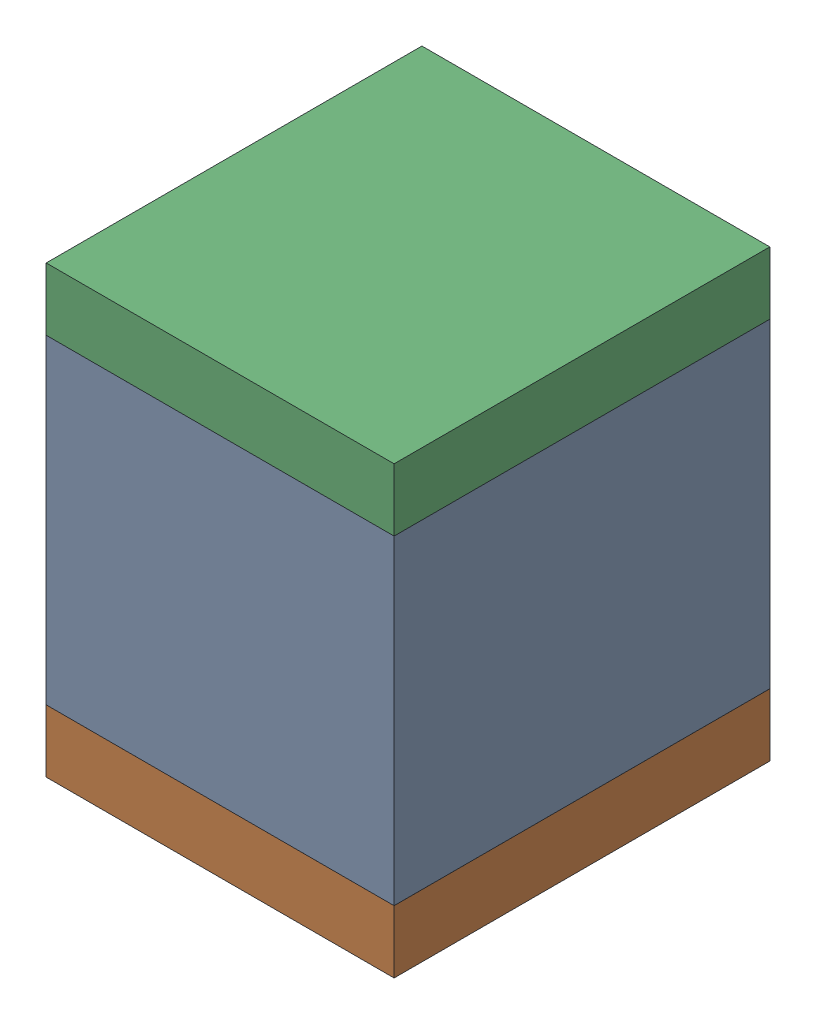
SolidWorks assembly C13, configuration ﾃﾞﾌｫﾙﾄ. Lengths in mm.
Overall size (2.5 3.2 2.7).
6 component instances, 2 part files, 0 mates.
Components (placement in the parent):
- 689260016-1: 689260016 [ﾃﾞﾌｫﾙﾄ] at (73.5 57.75 0) size (2.5 2.3 2.7)
  - Extruded_6-1: Extruded_6 [ﾃﾞﾌｫﾙﾄ] at origin size (2.5 2.3 2.7)
- 689260152-1: 689260152 [ﾃﾞﾌｫﾙﾄ] at (73.5001 56.375 0) size (2.5 0.45 2.7)
  - Extruded_7-1: Extruded_7 [ﾃﾞﾌｫﾙﾄ] at origin size (2.5 0.45 2.7)
- 689260152-2: 689260152 [ﾃﾞﾌｫﾙﾄ] at (73.5001 59.125 0) size (2.5 0.45 2.7)
  - Extruded_7-1: Extruded_7 [ﾃﾞﾌｫﾙﾄ] at origin size (2.5 0.45 2.7)
